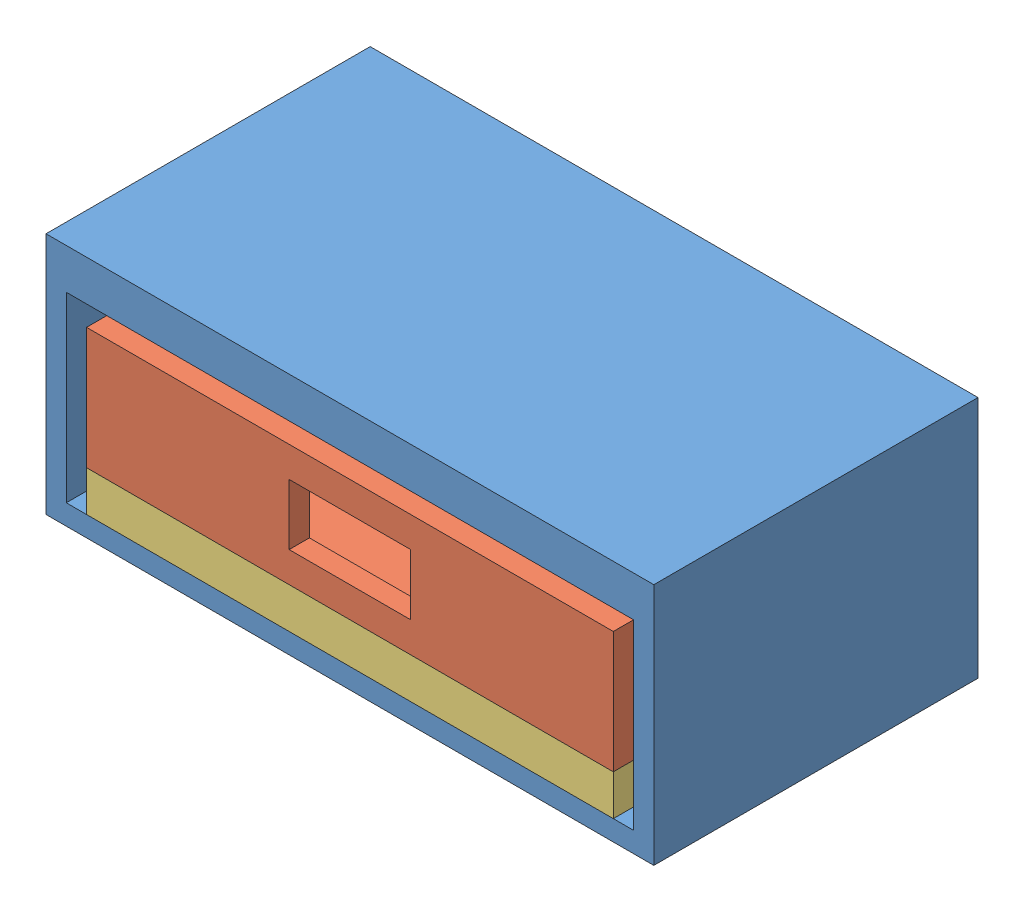
SolidWorks assembly Drawer Assembly, configuration Default. Lengths in mm.
Overall size (150 60 80).
3 component instances, 3 part files, 6 mates.
Components (placement in the parent):
- Outer Shell-1: Outer Shell [Default] at (-20.4123 53.948 152.0264) size (150 60 80)
- Drawer-1: Drawer [Default] at (-10.4123 98.948 152.0264) x (1 0 0) z (0 1 0) size (130 75 30)
- Drawer Support-1: Drawer Support [Default] at (-10.4123 68.948 77.0264) x (-1 0 0) z (0 1 0) size (130 75 10)
Mates (geometry in assembly coordinates):
- Coincident1: coincident anti-aligned: plane of Outer Shell-1 through (-20.4123 58.948 152.0264) normal (0 1 0); plane of Drawer Support-1 through (-10.4123 58.948 152.0264) normal (0 -1 0)
- Width1: width anti-aligned: plane of Outer Shell-1 through (124.5877 113.948 152.0264) normal (-1 0 0); plane of Outer Shell-1 through (-15.4123 113.948 152.0264) normal (1 0 0); plane of Drawer Support-1 through (119.5877 68.948 152.0264) normal (1 0 0); plane of Drawer Support-1 through (-10.4123 68.948 152.0264) normal (-1 0 0)
- Coincident2: coincident anti-aligned: plane of Drawer-1 through (-10.4123 68.948 77.0264) normal (0 -1 0); plane of Drawer Support-1 through (-10.4123 68.948 152.0264) normal (0 1 0)
- Width2: width anti-aligned: plane of Outer Shell-1 through (124.5877 113.948 152.0264) normal (-1 0 0); plane of Outer Shell-1 through (-15.4123 113.948 152.0264) normal (1 0 0); plane of Drawer-1 through (119.5877 98.948 77.0264) normal (1 0 0); plane of Drawer-1 through (-10.4123 98.948 77.0264) normal (-1 0 0)
- LimitDistance1: limit distance = 0 mm anti-aligned: plane of Outer Shell-1 through (-20.4123 113.948 77.0264) normal (0 0 1); plane of Drawer Support-1 through (-10.4123 68.948 77.0264) normal (0 0 -1)
- Linear/Linear Coupler1: linear coupler = 2 : 1 mm: plane of Drawer-1 through (-10.4123 98.948 152.0264) normal (0 0 1); plane of Drawer Support-1 through (-10.4123 68.948 152.0264) normal (0 0 1)
